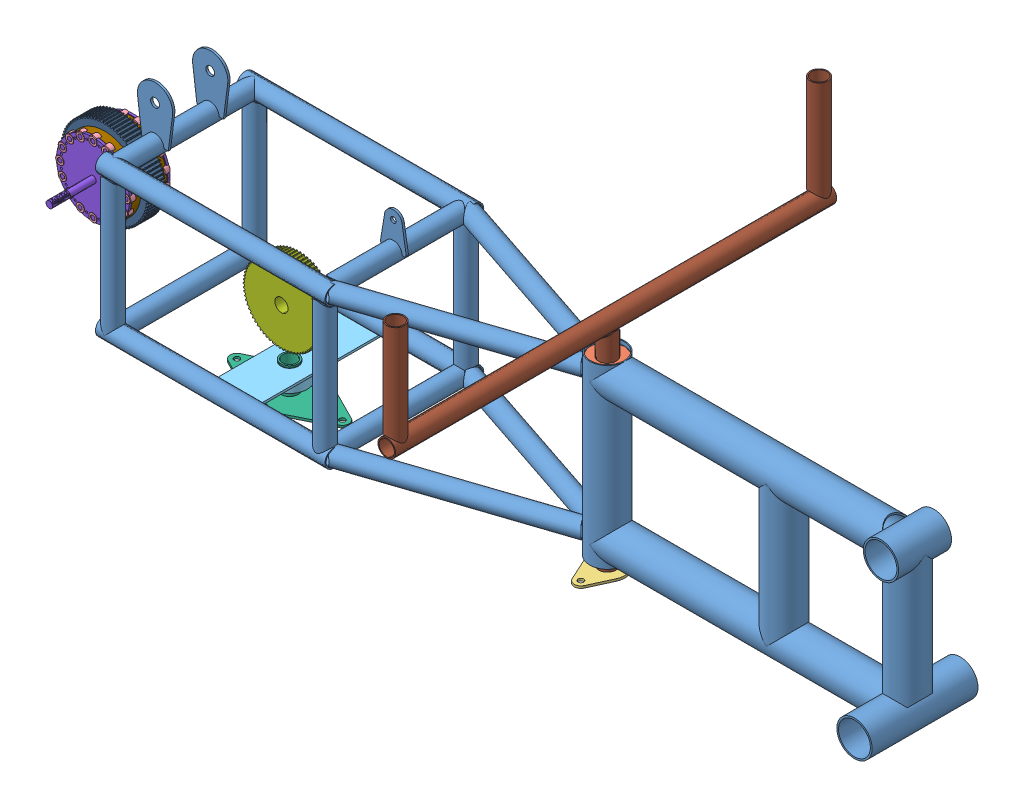
SolidWorks assembly Front_End_New, configuration Default. Lengths in mm.
Overall size (1423.68 905.32 635.01).
49 component instances, 11 part files, 24 mates.
Components (placement in the parent):
- 5M front dimension-1: 5M front dimension [Default<As Machined>] at (172.6528 497.1906 947.1311) size (1423.68 879.92 228.6)
- steering wheel bearing-1: steering wheel bearing [Default] at (782.2528 490.8406 1048.7311) size (49.4 12.7 49.4)
- steering wheel bearing-2: steering wheel bearing [Default] at (782.2528 719.4406 1048.7311) size (49.4 12.7 49.4)
- rear linkage turning plate-1: rear linkage turning plate [Default] at (782.3498 458.9886 1048.7304) x (0 0 -1) z (1 0 0) size (95.25 3.17 50.8)
- socket head cap screw_am-1: socket head cap screw_am [B18.3.1M - 6 x 1.0 x 16 Hex SHCS -- 16NHX] at (782.3498 449.8136 1042.3804) x (0 1 0) z (0 0 1) size (22 10 10)
- socket head cap screw_am-2: socket head cap screw_am [B18.3.1M - 6 x 1.0 x 16 Hex SHCS -- 16NHX] at (782.3498 449.8136 1055.0804) x (0 1 0) z (0 0 1) size (22 10 10)
- front linkage turning plate bracket-1: front linkage turning plate bracket [Default] at (325.0528 462.2656 1048.7311) x (0 0 -1) z (1 0 0) size (203.2 22.23 63.5)
- front linkage turning plate-1: front linkage turning plate [Default] at (325.0528 449.5656 1048.7311) x (0.002595 0 -0.999997) z (0.999997 0 0.002595) size (95.25 41.27 171.45)
- steering wheel bearing-3: steering wheel bearing [Default] at (325.0528 481.3156 1048.7311) size (49.4 12.7 49.4)
- final drive 5M 70T gear (assem)-1: final drive 5M 70T gear (assem) [Default] at (325.0528 577.9626 1061.1972) x (0.936138 0.351633 0) z (0 0 1) size (110.26 110.18 25)
- 80T Internal gear set-1: 80T Internal gear set [Default] at (17.6511 499.2857 902.3511) size (126.11 126.11 184)
  - 8 speed gearhub-1: 8 speed gearhub [Default] at (53.7721 99.7633 146.5613) size (105.2 105.2 184)
  - Assem 80T gear set-1: Assem 80T gear set [Default] at (25.1383 45.8156 52.8787) x (1 0 0) z (0 0 1) size (126.11 126.11 58.9)
    - final drive 5M 70T gear adaptor (final)-1: final drive 5M 70T gear adaptor (final) [Default] at (28.6339 53.9477 119.6327) size (104 104 13.6)
    - final drive 5M 70T gear adaptor (final)-2: final drive 5M 70T gear adaptor (final) [Default] at (28.6339 53.9477 67.7327) x (-0.980785 0.19509 0) z (0 0 -1) size (104 104 13.6)
    - socket head cap screw_am-1: socket head cap screw_am [B18.3.1M - 8 x 1.25 x 20 Hex SHCS -- 20NHX] at (-5.0456 87.6272 123.1327) x (0 0 -1) z (1 0 0) size (28 13 13)
    - socket head cap screw_am-2: socket head cap screw_am [B18.3.1M - 8 x 1.25 x 20 Hex SHCS -- 20NHX] at (10.4067 97.9521 123.1327) x (0 0 -1) z (1 0 0) size (28 13 13)
    - socket head cap screw_am-3: socket head cap screw_am [B18.3.1M - 8 x 1.25 x 20 Hex SHCS -- 20NHX] at (28.6339 101.5777 123.1327) x (0 0 -1) z (1 0 0) size (28 13 13)
    - socket head cap screw_am-4: socket head cap screw_am [B18.3.1M - 8 x 1.25 x 20 Hex SHCS -- 20NHX] at (46.8611 97.9521 123.1327) x (0 0 -1) z (1 0 0) size (28 13 13)
    - socket head cap screw_am-5: socket head cap screw_am [B18.3.1M - 8 x 1.25 x 20 Hex SHCS -- 20NHX] at (62.3134 87.6272 123.1327) x (0 0 -1) z (1 0 0) size (28 13 13)
    - socket head cap screw_am-6: socket head cap screw_am [B18.3.1M - 8 x 1.25 x 20 Hex SHCS -- 20NHX] at (-15.3705 72.1749 123.1327) x (0 0 -1) z (1 0 0) size (28 13 13)
    - socket head cap screw_am-7: socket head cap screw_am [B18.3.1M - 8 x 1.25 x 20 Hex SHCS -- 20NHX] at (-18.9961 53.9477 123.1327) x (0 0 -1) z (1 0 0) size (28 13 13)
    - socket head cap screw_am-8: socket head cap screw_am [B18.3.1M - 8 x 1.25 x 20 Hex SHCS -- 20NHX] at (72.6383 72.1749 123.1327) x (0 0 -1) z (1 0 0) size (28 13 13)
    - socket head cap screw_am-9: socket head cap screw_am [B18.3.1M - 8 x 1.25 x 20 Hex SHCS -- 20NHX] at (76.2639 53.9477 123.1327) x (0 0 -1) z (1 0 0) size (28 13 13)
    - socket head cap screw_am-10: socket head cap screw_am [B18.3.1M - 8 x 1.25 x 20 Hex SHCS -- 20NHX] at (62.3134 20.2682 123.1327) x (0 0 -1) z (1 0 0) size (28 13 13)
    - socket head cap screw_am-11: socket head cap screw_am [B18.3.1M - 8 x 1.25 x 20 Hex SHCS -- 20NHX] at (72.6383 35.7205 123.1327) x (0 0 -1) z (1 0 0) size (28 13 13)
    - socket head cap screw_am-12: socket head cap screw_am [B18.3.1M - 8 x 1.25 x 20 Hex SHCS -- 20NHX] at (46.8611 9.9433 123.1327) x (0 0 -1) z (1 0 0) size (28 13 13)
    - socket head cap screw_am-13: socket head cap screw_am [B18.3.1M - 8 x 1.25 x 20 Hex SHCS -- 20NHX] at (28.6339 6.3177 123.1327) x (0 0 -1) z (1 0 0) size (28 13 13)
    - socket head cap screw_am-14: socket head cap screw_am [B18.3.1M - 8 x 1.25 x 20 Hex SHCS -- 20NHX] at (10.4067 9.9433 123.1327) x (0 0 -1) z (1 0 0) size (28 13 13)
    - socket head cap screw_am-15: socket head cap screw_am [B18.3.1M - 8 x 1.25 x 20 Hex SHCS -- 20NHX] at (-5.0456 20.2682 123.1327) x (0 0 -1) z (1 0 0) size (28 13 13)
    - socket head cap screw_am-16: socket head cap screw_am [B18.3.1M - 8 x 1.25 x 20 Hex SHCS -- 20NHX] at (-15.3705 35.7205 123.1327) x (0 0 -1) z (1 0 0) size (28 13 13)
    - socket head cap screw_am-17: socket head cap screw_am [B18.3.1M - 8 x 1.25 x 20 Hex SHCS -- 20NHX] at (37.926 100.6625 64.2327) x (0 0 1) z (-1 0 0) size (28 13 13)
    - socket head cap screw_am-18: socket head cap screw_am [B18.3.1M - 8 x 1.25 x 20 Hex SHCS -- 20NHX] at (19.3417 100.6625 64.2327) x (0 0 1) z (-1 0 0) size (28 13 13)
    - socket head cap screw_am-19: socket head cap screw_am [B18.3.1M - 8 x 1.25 x 20 Hex SHCS -- 20NHX] at (2.1721 93.5506 64.2327) x (0 0 1) z (-1 0 0) size (28 13 13)
    - socket head cap screw_am-20: socket head cap screw_am [B18.3.1M - 8 x 1.25 x 20 Hex SHCS -- 20NHX] at (-10.969 80.4095 64.2327) x (0 0 1) z (-1 0 0) size (28 13 13)
    - socket head cap screw_am-21: socket head cap screw_am [B18.3.1M - 8 x 1.25 x 20 Hex SHCS -- 20NHX] at (-18.0809 63.2398 64.2327) x (0 0 1) z (-1 0 0) size (28 13 13)
    - socket head cap screw_am-22: socket head cap screw_am [B18.3.1M - 8 x 1.25 x 20 Hex SHCS -- 20NHX] at (-18.0809 44.6555 64.2327) x (0 0 1) z (-1 0 0) size (28 13 13)
    - socket head cap screw_am-23: socket head cap screw_am [B18.3.1M - 8 x 1.25 x 20 Hex SHCS -- 20NHX] at (-10.969 27.4859 64.2327) x (0 0 1) z (-1 0 0) size (28 13 13)
    - socket head cap screw_am-24: socket head cap screw_am [B18.3.1M - 8 x 1.25 x 20 Hex SHCS -- 20NHX] at (55.0957 93.5506 64.2327) x (0 0 1) z (-1 0 0) size (28 13 13)
    - socket head cap screw_am-25: socket head cap screw_am [B18.3.1M - 8 x 1.25 x 20 Hex SHCS -- 20NHX] at (68.2368 80.4095 64.2327) x (0 0 1) z (-1 0 0) size (28 13 13)
    - socket head cap screw_am-26: socket head cap screw_am [B18.3.1M - 8 x 1.25 x 20 Hex SHCS -- 20NHX] at (75.3487 63.2398 64.2327) x (0 0 1) z (-1 0 0) size (28 13 13)
    - socket head cap screw_am-27: socket head cap screw_am [B18.3.1M - 8 x 1.25 x 20 Hex SHCS -- 20NHX] at (2.1721 14.3448 64.2327) x (0 0 1) z (-1 0 0) size (28 13 13)
    - socket head cap screw_am-28: socket head cap screw_am [B18.3.1M - 8 x 1.25 x 20 Hex SHCS -- 20NHX] at (19.3417 7.2329 64.2327) x (0 0 1) z (-1 0 0) size (28 13 13)
    - socket head cap screw_am-29: socket head cap screw_am [B18.3.1M - 8 x 1.25 x 20 Hex SHCS -- 20NHX] at (37.926 7.2329 64.2327) x (0 0 1) z (-1 0 0) size (28 13 13)
    - socket head cap screw_am-30: socket head cap screw_am [B18.3.1M - 8 x 1.25 x 20 Hex SHCS -- 20NHX] at (68.2368 27.4859 64.2327) x (0 0 1) z (-1 0 0) size (28 13 13)
    - socket head cap screw_am-31: socket head cap screw_am [B18.3.1M - 8 x 1.25 x 20 Hex SHCS -- 20NHX] at (75.3487 44.6555 64.2327) x (0 0 1) z (-1 0 0) size (28 13 13)
    - socket head cap screw_am-32: socket head cap screw_am [B18.3.1M - 8 x 1.25 x 20 Hex SHCS -- 20NHX] at (55.0957 14.3448 64.2327) x (0 0 1) z (-1 0 0) size (28 13 13)
    - final drive 5M 80T gear-1: final drive 5M 80T gear [Default] at (28.6339 53.9477 106.1827) size (126.11 126.11 25)
- New_Steering-1: New_Steering [Default<As Machined>] at (782.2528 446.3906 1048.7311) x (-0.000234 0 -1) z (1 0 -0.000234) size (635 457.2 25.4)
Mates (geometry in assembly coordinates):
- Concentric1: concentric aligned: circle of 5M front dimension-1; circle of Front crank pulley bar-1
- Concentric2: concentric anti-aligned: circle of 5M front dimension-1; circle of steering wheel bearing-1
- Coincident2: coincident anti-aligned: plane of 5M front dimension-1 through (782.2528 490.8406 1048.7311) normal (0 -1 0); circle of steering wheel bearing-1
- Concentric3: concentric anti-aligned: circle of 5M front dimension-1; circle of steering wheel bearing-2
- Coincident3: coincident aligned: circle of 5M front dimension-1; plane of steering wheel bearing-2 through (782.2528 706.7406 1048.7311) normal (0 -1 0)
- Concentric4: concentric aligned: circle of steering wheel-1; circle of steering wheel bearing-1
- Coincident4: coincident aligned: circle of steering wheel-1; plane of steering wheel bearing-2 through (782.2528 719.4406 1048.7311) normal (0 1 0)
- Concentric5: concentric aligned: circle of steering wheel-1; circle of rear linkage turning plate-1
- Coincident5: coincident aligned: circle of steering wheel-1; plane of rear linkage turning plate-1 through (782.3498 458.9886 1086.8304) normal (0 1 0)
- Concentric6: concentric anti-aligned: cylinder of rear linkage turning plate-1 through (782.3498 455.8136 1042.3804) axis (0 1 0) radius 3; cylinder of socket head cap screw_am-1 through (782.3498 418.0636 1042.3804) axis (0 -1 0) radius 5
- Coincident6: coincident anti-aligned: plane of rear linkage turning plate-1 through (782.3498 455.8136 1086.8304) normal (0 -1 0); plane of socket head cap screw_am-1 through (777.3498 455.8136 1042.3804) normal (0 1 0)
- Concentric7: concentric anti-aligned: cylinder of rear linkage turning plate-1 through (782.3498 455.8136 1055.0804) axis (0 1 0) radius 3; cylinder of socket head cap screw_am-2 through (782.3498 418.0636 1055.0804) axis (0 -1 0) radius 5
- Coincident7: coincident anti-aligned: plane of rear linkage turning plate-1 through (782.3498 455.8136 1086.8304) normal (0 -1 0); plane of socket head cap screw_am-2 through (777.3498 455.8136 1055.0804) normal (0 1 0)
- Coincident8: coincident: line of 5M front dimension-1 through (172.6528 497.1906 1150.3311) axis (1 0 0); line of front linkage turning plate bracket-1 through (293.3028 484.4906 1150.3311) axis (1 0 0)
- Coincident9: coincident: cylinder of 5M front dimension-1 through (172.6528 497.1906 947.1311) axis (1 0 0) radius 12.7; line of front linkage turning plate bracket-1 through (356.8028 484.4906 947.1311) axis (-1 0 0)
- Concentric8: concentric aligned: circle of front linkage turning plate bracket-1; circle of steering wheel bearing-3
- Coincident10: coincident anti-aligned: plane of front linkage turning plate bracket-1 through (325.0528 481.3156 1048.7311) normal (0 -1 0); circle of steering wheel bearing-3
- Concentric9: concentric aligned: circle of front linkage turning plate-1; circle of steering wheel bearing-3
- Coincident11: coincident anti-aligned: circle of front linkage turning plate-1; plane of steering wheel bearing-3 through (325.0528 468.6156 1048.7311) normal (0 -1 0)
- Coincident13: coincident anti-aligned: circle of steering wheel bearing-2; cylinder of New_Steering-1 through (782.2528 719.4406 1048.7311) axis (0 -1 0) radius 12.5
- Coincident14: coincident anti-aligned: plane of steering wheel bearing-2 through (782.2528 719.4406 1048.7311) normal (0 1 0); plane of New_Steering-1 through (782.2528 719.4406 1048.7311) normal (0 -1 0)
- Coincident17: coincident: plane of 5M front dimension-1; plane of front linkage turning plate bracket-1 through (293.3028 484.4906 1150.3311) normal (0 0 1)
- Distance3: distance = 152.9283 mm: point of front linkage turning plate bracket-1
- Concentric10: concentric aligned: circle of 5M front dimension-1; circle of final drive 5M 70T gear (assem)-1
